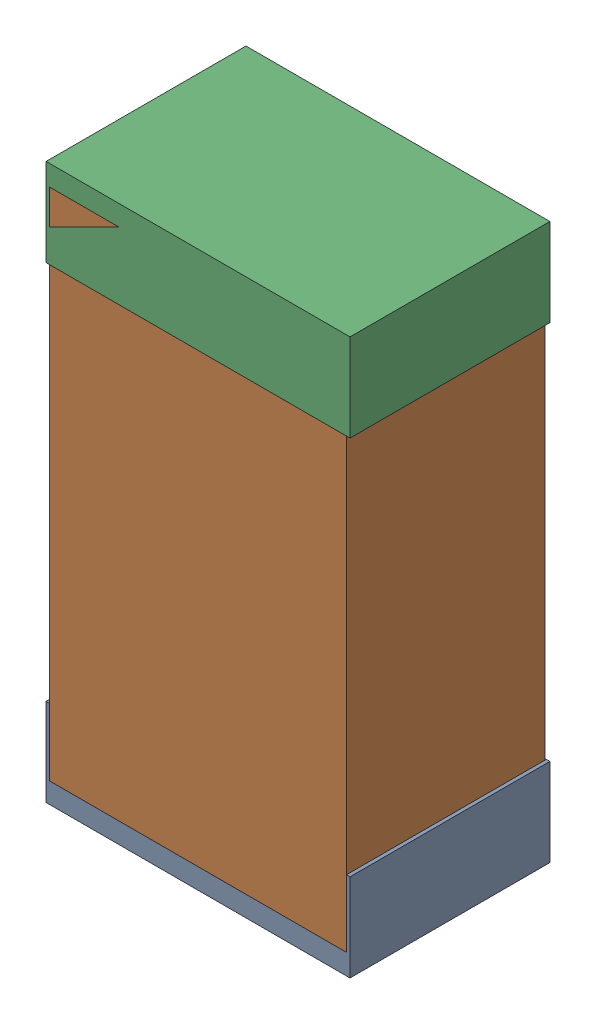
SolidWorks assembly R56Kanaloa_v2.0.0_Motor, configuration Default. Lengths in mm.
Overall size (1.3 2.38 0.85).
6 component instances, 2 part files, 0 mates.
Components (placement in the parent):
- 330415056-1: 330415056 [Default] at (138.938 148.606 -1.9574) size (1.3 0.38 0.85)
  - Extruded_2-1: Extruded_2 [Default] at origin size (1.3 0.38 0.85)
- 334787376-1: 334787376 [Default] at (138.938 149.606 -1.9524) size (1.27 2.2 0.85)
  - Extruded_16-1: Extruded_16 [Default] at origin size (1.27 2.2 0.85)
- 330415056-2: 330415056 [Default] at (138.938 150.606 -1.9574) size (1.3 0.38 0.85)
  - Extruded_2-1: Extruded_2 [Default] at origin size (1.3 0.38 0.85)
